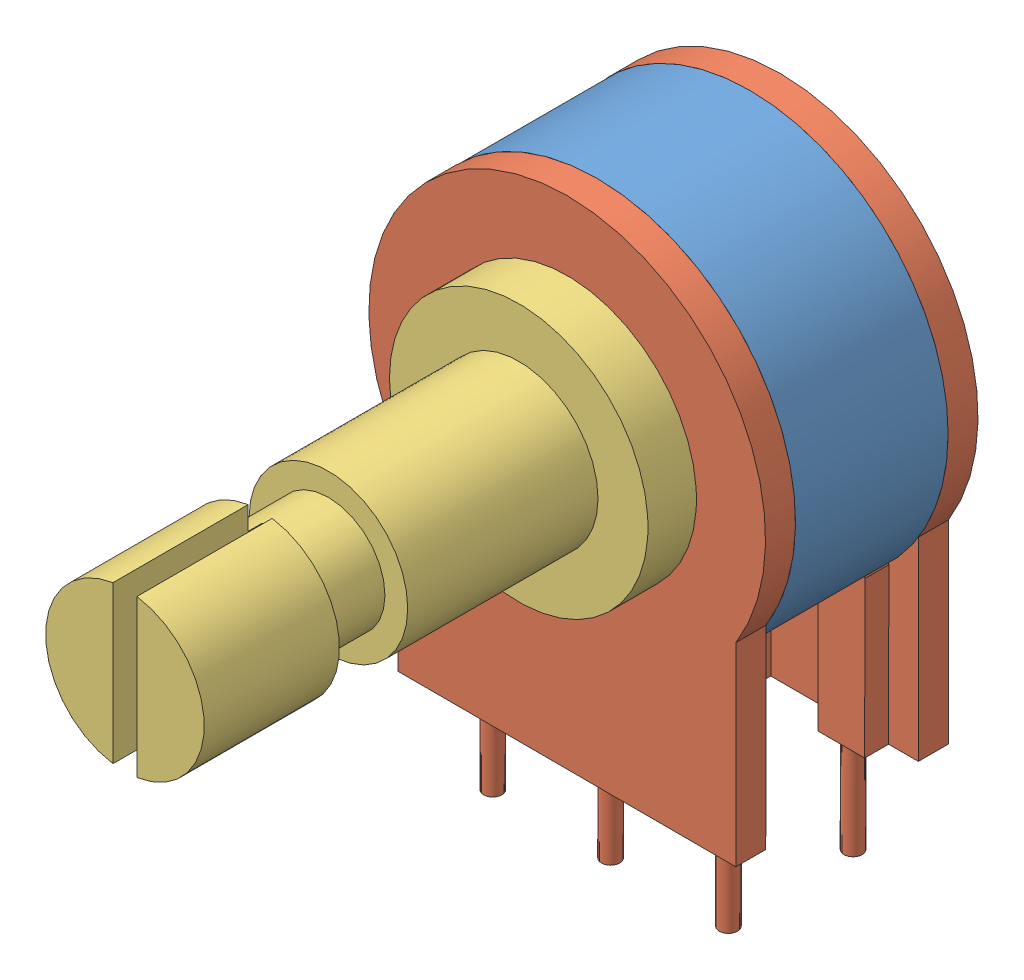
SolidWorks assembly Dual Pot Long Shaft, configuration Default. Lengths in mm.
Overall size (16.87 25.22 27.79).
4 component instances, 3 part files, 7 mates.
Components (placement in the parent):
- Body-1: Body [Default] at (-8.6298 0.3105 1.1044) size (16.84 16.84 6.48)
- Waffer-1: Waffer [Default] at (-8.6298 0.3105 -0.1656) x (0.999999 -0.001262 0) z (0 0 1) size (16.84 25.2 2.29)
- Waffer-2: Waffer [Default] at (-8.6298 0.3105 8.8514) x (-0.999999 0.001262 0) z (0 0 -1) size (16.84 25.2 2.29)
- Shaft-1: Shaft [Default] at (-8.6298 0.3105 8.8514) size (10.97 10.97 18.77)
Mates (geometry in assembly coordinates):
- Coincident1: coincident anti-aligned: plane of Body-1 through (-8.6298 0.3105 1.1044) normal (0 0 -1); plane of Waffer-1 through (-8.6298 0.3105 1.1044) normal (0 0 1)
- Coincident2: coincident aligned: circle of Body-1; circle of Waffer-1
- Coincident3: coincident anti-aligned: plane of Body-1 through (-8.6298 0.3105 7.5814) normal (0 0 1); plane of Waffer-2 through (-8.6298 0.3105 7.5814) normal (0 0 -1)
- Coincident4: coincident anti-aligned: circle of Body-1; circle of Waffer-2
- Parallel1: parallel anti-aligned: line of Waffer-1 through (-15.8074 -4.0918 1.1044) axis (-0.001262 -0.999999 0); line of Waffer-2 through (-15.8178 -12.3423 8.8514) axis (0.001262 0.999999 0)
- Coincident6: coincident anti-aligned: plane of Waffer-2 through (-8.6298 0.3105 8.8514) normal (0 0 1); plane of Shaft-1 through (-8.6298 0.3105 8.8514) normal (0 0 -1)
- Concentric1: concentric: circle of Waffer-2; circle of Shaft-1
